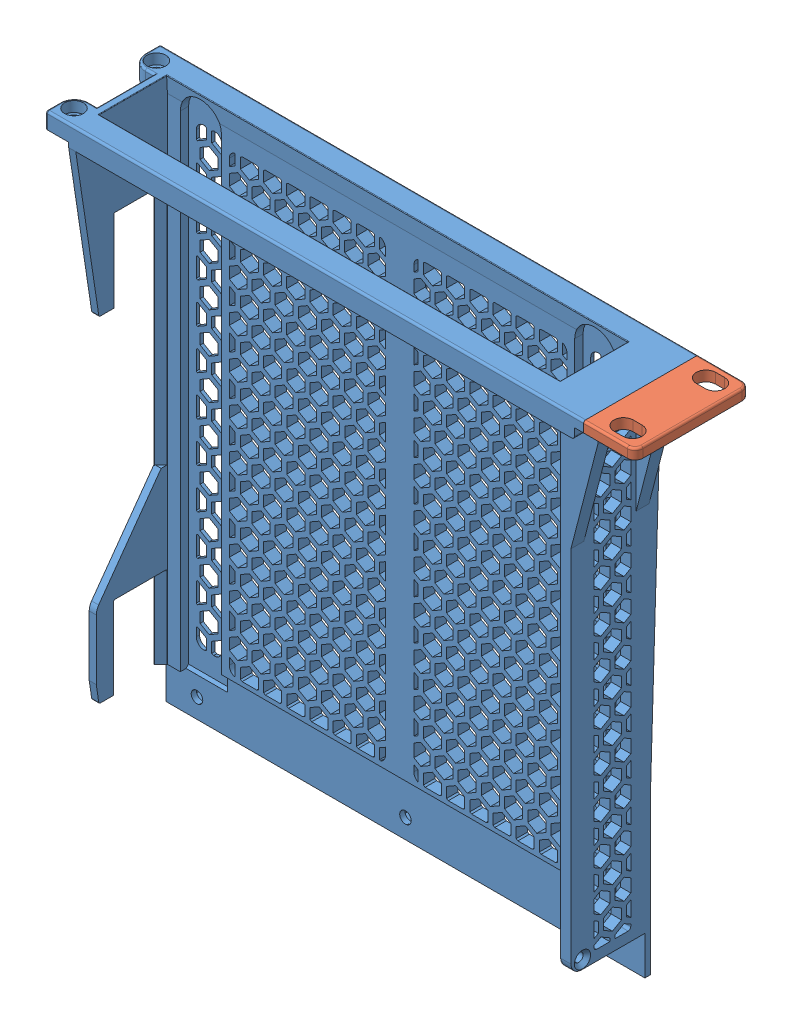
SolidWorks assembly Left Bracket (With Ear), configuration Standard. Lengths in mm.
Overall size (228.92 213.01 44.5).
2 component instances, 2 part files, 6 mates.
Components (placement in the parent):
- Left Bracket (With Ear)-1: Left Bracket (With Ear) [Standard] at (55.0369 -294.4118 -21.21) size (208.92 213.01 44.5)
- Left Ear-1: Left Ear [Standard] at (55.0369 -294.4118 -21.21) size (20 4 44.5)
Mates (geometry in assembly coordinates):
- Deckungsgleich2: coincident aligned: plane of Left Bracket (With Ear)-1 through (19 0 22.25) normal (0 1 0); plane of Left Ear-1 through (19 0 22.25) normal (0 1 0)
- Deckungsgleich3: coincident aligned: plane of Left Bracket (With Ear)-1 through (-6 -4.4 44.5) normal (0 0 1); plane of Left Ear-1 through (-6 -4.4 44.5) normal (0 0 1)
- Deckungsgleich4: coincident anti-aligned: plane of Left Bracket (With Ear)-1 through (199.75 -106.4994 22.25) normal (1 0 0); plane of Left Ear-1 through (199.75 -106.4994 22.25) normal (-1 0 0)
- Deckungsgleich5: coincident anti-aligned: plane of ? through (19 -4.4 0) normal (0 0 -1)
- Deckungsgleich6: coincident aligned: plane of ? through (19 0 22.25) normal (0 1 0)
- Deckungsgleich7: coincident anti-aligned: plane of ? through (0 -181.8827 -9.4707) normal (-1 0 0)
